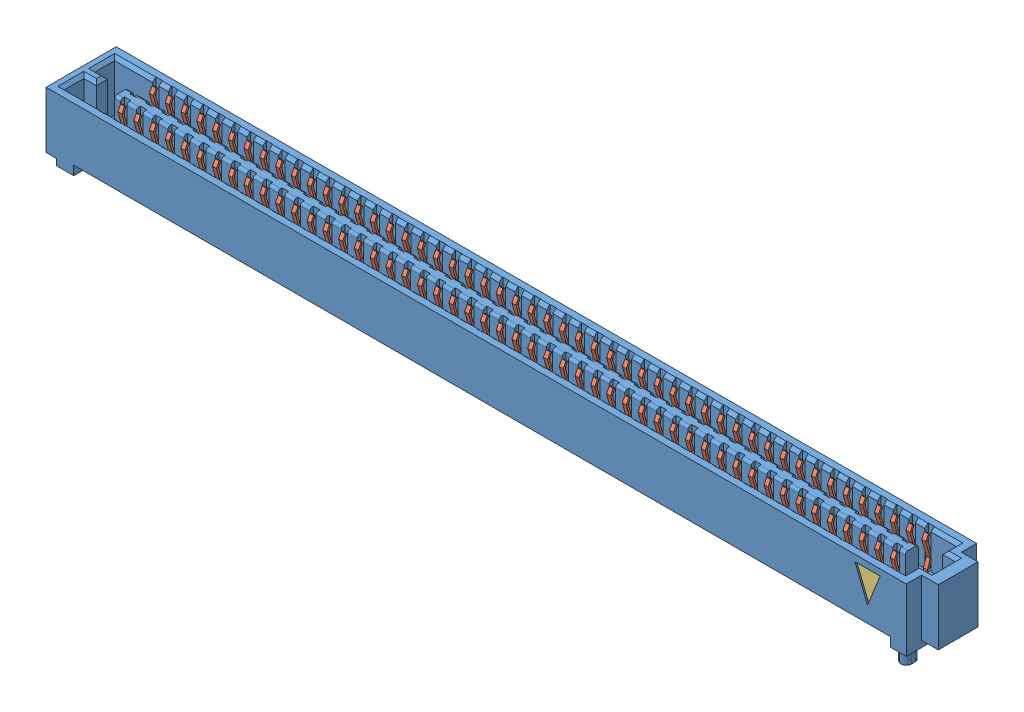
SolidWorks assembly Assem7, configuration Default. Lengths in mm.
Overall size (70.66 6.32 5.66).
5 component instances, 4 part files, 3 mates.
Components (placement in the parent):
- SEAF_50_05_0_L_04_2_A_K_TR-1: SEAF_50_05_0_L_04_2_A_K_TR [Default] at (0.254 0.7366 0) size (70.66 6.32 5.66)
  - _SEAF_50_05_0_L_04_1_A_0_K_TR_BODY_2_2-1: _SEAF_50_05_0_L_04_1_A_0_K_TR_BODY_2_2 [Default] at origin size (70.66 6.32 5.66)
  - _SEAF_50_05_0_L_04_1_A_0_K_TR_cCON2_4-1: _SEAF_50_05_0_L_04_1_A_0_K_TR_cCON2_4 [Default] at origin size (62.55 4.65 5.41)
  - _SEAF_04_K_PAD_6-1: _SEAF_04_K_PAD_6 [Default] at (-0.2286 4.318 0) size (6.5 0.13 6.5) (hidden)
  - _SEAF_TRIANGLE_FIRST_PIN_8-1: _SEAF_TRIANGLE_FIRST_PIN_8 [Default] at (30.861 0.762 2.5781) size (2.03 2.54 0.13)
Mates (geometry in assembly coordinates):
- Coincident1: coincident: plane of ? through (0.254 0 0) normal (0 -1 0)
- Coincident2: coincident: plane of ? through (0 0.7366 0) normal (-1 0 0)
- Coincident3: coincident: plane of ? through (0.254 0.7366 0) normal (0 0 -1)
